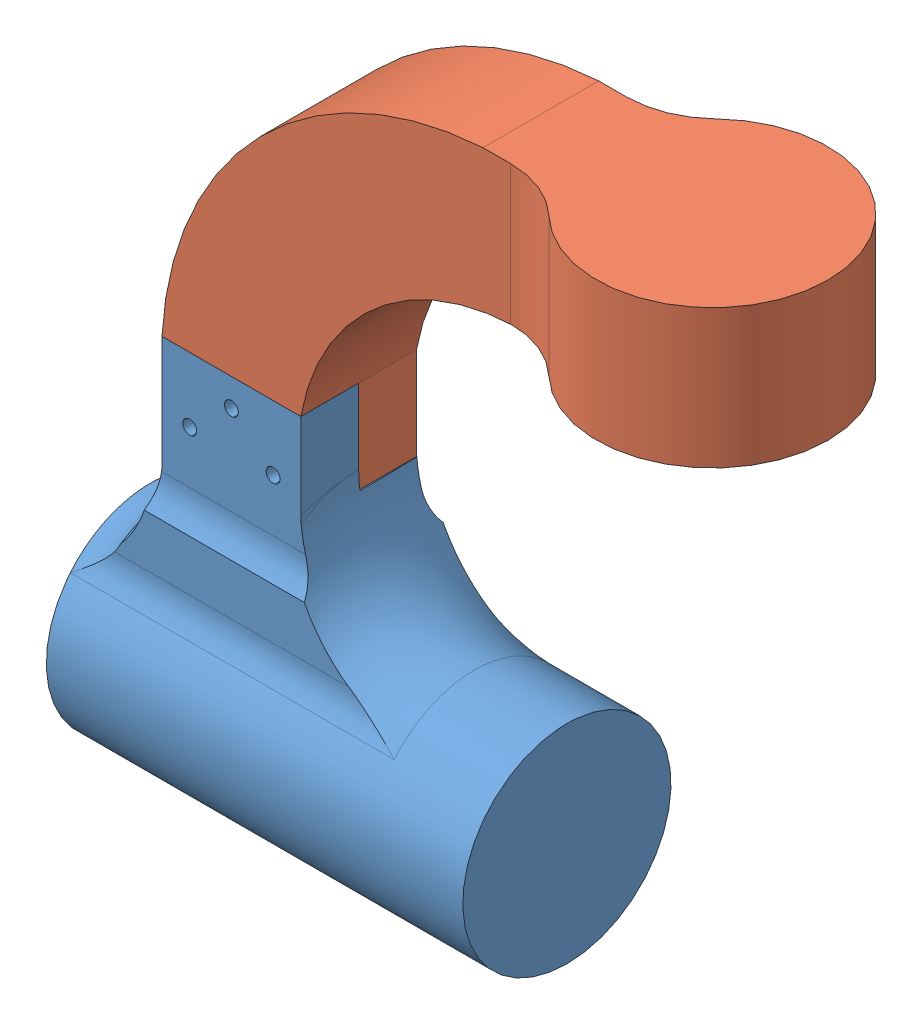
SolidWorks assembly Wheel_Steer_Assembly, configuration Default. Lengths in mm.
Overall size (146.44 156.21 50).
2 component instances, 2 part files, 6 mates.
Components (placement in the parent):
- Motor_holder_end_wheels-1: Motor_holder_end_wheels [Default] at (-15 -43.7083 12.5) x (0 1 0) z (1 0 0) size (86.21 45 90)
- Steer_to_motor_holder-1: Steer_to_motor_holder [Default] at origin size (131.61 90 50)
Mates (geometry in assembly coordinates):
- Coincident5: coincident aligned: plane of Steer_to_motor_holder-1 through (0 0 0) normal (0 0 1)
- Coincident6: coincident aligned: plane of Steer_to_motor_holder-1 through (0 0 0) normal (0 1 0)
- Coincident7: coincident aligned: plane of Steer_to_motor_holder-1 through (0 0 0) normal (1 0 0)
- Coincident8: coincident anti-aligned: plane of Motor_holder_end_wheels-1 through (48 20 12.5) normal (0 0 -1); plane of Steer_to_motor_holder-1 through (49 0 12.5) normal (0 0 1)
- Coincident9: coincident anti-aligned: plane of Motor_holder_end_wheels-1 through (48 20 25) normal (0 1 0); plane of Steer_to_motor_holder-1 through (49 20 12.5) normal (0 -1 0)
- Coincident10: coincident aligned: plane of Motor_holder_end_wheels-1 through (30 -10 0) normal (1 0 0); plane of Steer_to_motor_holder-1 through (30 0 25) normal (1 0 0)
